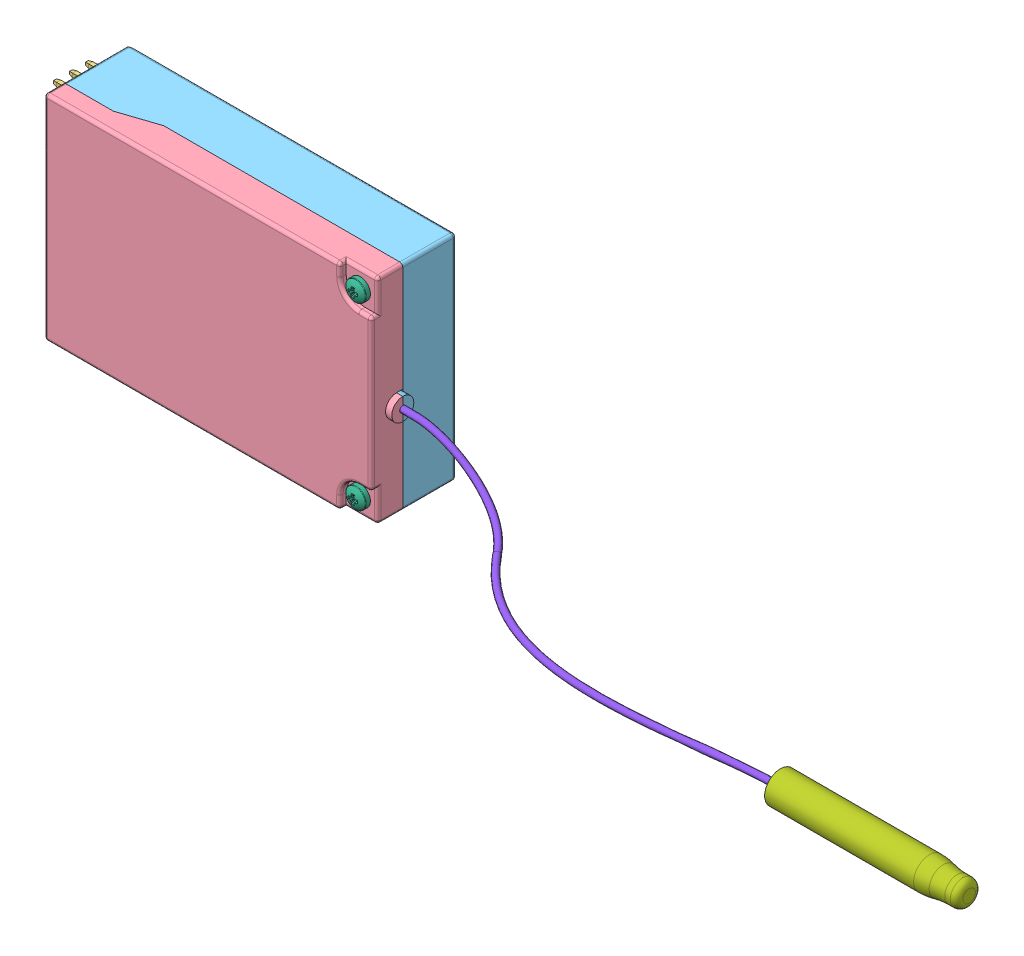
SolidWorks assembly TURNIGY - Recepteur 9X, configuration Défaut. Lengths in mm.
Overall size (156 34 24.61).
19 component instances, 8 part files, 25 mates.
Components (placement in the parent):
- Planche 1-1: Planche 1 [Défaut] at (0 0 5.25) size (32 31 1.5)
- Planche 2-1: Planche 2 [Défaut] at (-16.75 0 6.75) x (0 1 0) z (1 0 0) size (31 10.5 1.5)
- Broche Vertical 1x3-1: Broche Vertical 1x3 [Default] at (-18.75 14.25 9.29) x (0 0 1) z (-1 0 0) size (7.62 2.5 11)
- Broche Vertical 1x3-10: Broche Vertical 1x3 [Default] at (-18.75 -14.25 9.29) x (0 0 1) z (-1 0 0) size (7.62 2.5 11)
- Broche Vertical 1x3-11: Broche Vertical 1x3 [Default] at (-18.75 11.25 9.29) x (0 0 1) z (-1 0 0) size (7.62 2.5 11)
- Broche Vertical 1x3-12: Broche Vertical 1x3 [Default] at (-18.75 8.25 9.29) x (0 0 1) z (-1 0 0) size (7.62 2.5 11)
- Broche Vertical 1x3-13: Broche Vertical 1x3 [Default] at (-18.75 5.25 9.29) x (0 0 1) z (-1 0 0) size (7.62 2.5 11)
- Broche Vertical 1x3-14: Broche Vertical 1x3 [Default] at (-18.75 2.25 9.29) x (0 0 1) z (-1 0 0) size (7.62 2.5 11)
- Broche Vertical 1x3-15: Broche Vertical 1x3 [Default] at (-18.75 -11.25 9.29) x (0 0 1) z (-1 0 0) size (7.62 2.5 11)
- Broche Vertical 1x3-16: Broche Vertical 1x3 [Default] at (-18.75 -8.25 9.29) x (0 0 1) z (-1 0 0) size (7.62 2.5 11)
- Broche Vertical 1x3-17: Broche Vertical 1x3 [Default] at (-18.75 -5.25 9.29) x (0 0 1) z (-1 0 0) size (7.62 2.5 11)
- Broche Vertical 1x3-18: Broche Vertical 1x3 [Default] at (-18.75 -2.25 9.29) x (0 0 1) z (-1 0 0) size (7.62 2.5 11)
- Coque inférieur-1: Coque inférieur [Défaut] at (3.5 0 14.5) x (1 0 0) z (0 0 -1) size (53 34 5)
- Coque Supérieur-1: Coque Supérieur [Défaut] at (3.5 0 12.5) x (1 0 0) z (0 0 -1) size (53.03 34 13.03)
- pan head cross recess screw_din-2: pan head cross recess screw_din [ISO 7045 - M1.6 x 10 - Z --- 10N] at (26.75 -14.25 14.8) x (0 0 -1) z (1 0 0) size (11.27 3.2 3.2)
- pan head cross recess screw_din-3: pan head cross recess screw_din [ISO 7045 - M1.6 x 10 - Z --- 10N] at (26.75 14.25 14.8) x (0 0 -1) z (1 0 0) size (11.27 3.2 3.2)
- Antenne-1: Antenne [Défaut] at (112.5 -14.5 20) x (0 1 0) z (0 0 -1) size (5 30 5)
- Cable_3-SA_Récepteur 9X-1: Cable_3-SA_Récepteur 9X [Défaut] at origin size (74 15.25 15.57)
  - Cble^Cable_3-SA_Récepteur 9X-1: Cble^Cable_3-SA_Récepteur 9X [Défaut] at origin size (74 15.25 15.57) (virtual)
Mates (geometry in assembly coordinates):
- Coïncidente1: coincident anti-aligned: plane of Planche 1-1 through (-16 15.5 6) normal (-1 0 0); plane of Planche 2-1 through (-16 0 6.75) normal (1 0 0)
- Distance2: distance = 6 mm aligned: plane of Planche 1-1 through (0 0 6) normal (0 0 1); plane of Planche 2-1 through (-16 -15.5 12) normal (0 0 1)
- Coïncidente4: coincident aligned: plane of Planche 1-1 through (-16 -15.5 6) normal (0 -1 0); plane of Planche 2-1 through (-16 -15.5 12) normal (0 -1 0)
- Coïncidente32: coincident aligned: plane of Broche Vertical 1x3-1 through (-20 15.1464 2.94) normal (0 0 -1); plane of Broche Vertical 1x3-10 through (-20 -13.3536 2.94) normal (0 0 -1)
- Coïncidente41: coincident aligned: plane of Broche Vertical 1x3-1 through (-20 15.5 5.48) normal (-1 0 0); plane of Broche Vertical 1x3-10 through (-20 -13 5.48) normal (-1 0 0)
- Coïncidente42: coincident aligned: plane of Broche Vertical 1x3-1 through (-20 15.5 5.8336) normal (0 1 0); plane of Planche 2-1 through (-16 15.5 12) normal (0 1 0)
- Coïncidente46: coincident: plane of Planche 2-1 through (-17.5 0 6.75) normal (-1 0 0); line of Broche Vertical 1x3-1 through (-17.5 15.5 7.6664) axis (0 0 -1)
- Distance3: distance = 0.32 mm anti-aligned: plane of Broche Vertical 1x3-1 through (-15 13.93 6.43) normal (0 0 -1); plane of Planche 2-1
- Coïncidente48: coincident aligned: plane of Planche 2-1 through (-16 -15.5 12) normal (0 -1 0); plane of Broche Vertical 1x3-10 through (-20 -15.5 5.8336) normal (0 -1 0)
- Coïncidente49: coincident aligned: plane of Coque inférieur-1 through (-22.5 17 9.5) normal (0 1 0); plane of Coque Supérieur-1 through (-22.5 17 0) normal (0 1 0)
- Coïncidente50: coincident aligned: plane of Coque inférieur-1 through (29.5 -17 9.5) normal (1 0 0); plane of Coque Supérieur-1 through (29.5 -17 0) normal (1 0 0)
- Coïncidente57: coincident anti-aligned: plane of Broche Vertical 1x3-10 through (-20 -13 8.02) normal (-1 0 0); plane of Coque Supérieur-1 through (-20 0 12.5) normal (1 0 0)
- Coïncidente59: coincident anti-aligned: plane of Planche 1-1 through (-16 -15.5 6) normal (0 -1 0); plane of Coque Supérieur-1 through (-22.5 -15.5 0) normal (0 1 0)
- Coïncidente62: coincident anti-aligned: plane of Coque inférieur-1 through (-8.5 0 9.5) normal (-0.316228 0 -0.948683); plane of Coque Supérieur-1 through (-14.5 -17 11.5) normal (0.316228 0 0.948683)
- Distance4: distance = 3.25 mm aligned: plane of Planche 2-1; plane of Coque Supérieur-1 through (30.501 0 3.5) normal (0 0 1)
- Coaxiale8: concentric anti-aligned: cylinder of Coque inférieur-1 through (26.75 -14.25 18.6569) axis (0 0 -1) radius 1; cylinder of pan head cross recess screw_din-2 through (26.75 -14.25 40.2) axis (0 0 1) radius 1.6
- Coïncidente69: coincident anti-aligned: plane of Coque inférieur-1 through (27.5 -15 13.5) normal (0 0 1); plane of pan head cross recess screw_din-2 through (26.75 -13.45 13.5) normal (0 0 -1)
- Coaxiale9: concentric anti-aligned: cylinder of Coque inférieur-1 through (26.75 14.25 18.6569) axis (0 0 -1) radius 1; cylinder of pan head cross recess screw_din-3 through (26.75 14.25 40.2) axis (0 0 1) radius 1.6
- Coïncidente70: coincident anti-aligned: plane of Coque inférieur-1 through (27.5 15 13.5) normal (0 0 1); plane of pan head cross recess screw_din-3 through (26.75 15.05 13.5) normal (0 0 -1)
- Coïncidente71: coincident aligned: plane of Planche 1-1 through (0 0 5.25) normal (0 1 0); plane of assembly through (0 0 0) normal (0 1 0)
- Coïncidente72: coincident aligned: plane of Planche 1-1 through (0 0 5.25) normal (1 0 0); plane of assembly through (0 0 0) normal (1 0 0)
- Coïncidente73: coincident anti-aligned: plane of Coque Supérieur-1 through (3.5 0 0) normal (0 0 -1); plane of assembly through (0 0 0) normal (0 0 1)
- Distance8: distance = 2.5 mm anti-aligned: plane of Antenne-1; plane of Coque Supérieur-1 through (-22.5 -17 0) normal (0 -1 0)
- Distance9: distance = 100 mm anti-aligned: plane of Antenne-1 through (100 -15 20) normal (-1 0 0); plane of assembly through (0 0 0) normal (1 0 0)
- Distance10: distance = 20 mm anti-aligned: plane of assembly through (0 0 0) normal (0 0 1); plane of Antenne-1 through (112.5 -14.5 20) normal (0 0 -1)
